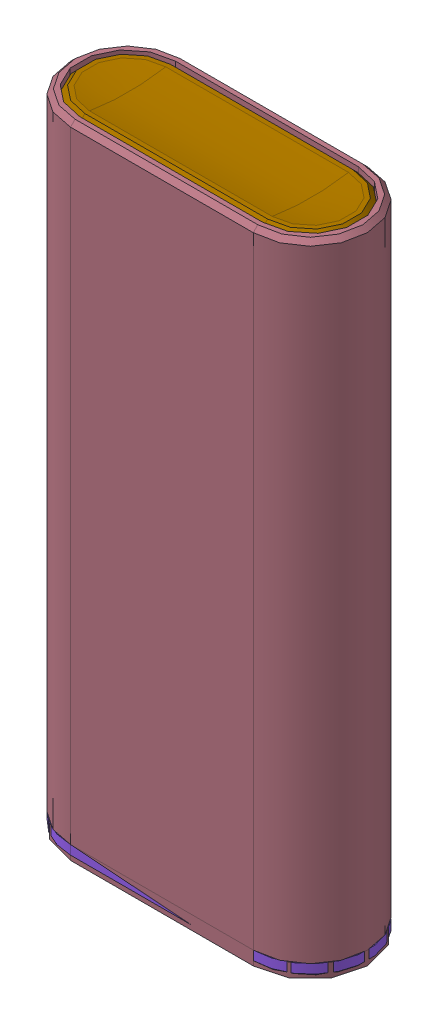
SolidWorks assembly case, configuration Default. Lengths in mm.
Overall size (65 140.17 25).
27 component instances, 14 part files, 68 mates.
Components (placement in the parent):
- touch_clamp-1: touch_clamp [Closed] at origin size (21.45 19 7)
  - touch_clamp-1: touch_clamp [Closed] at origin size (10.9 16.59 6.9)
  - touch_plate-1: touch_plate [Default] at (0 19 0) x (-1 0 0) z (0 0 1) size (21.45 7.3 7)
- 90710A030_TYPE 18-8 SS THIN HEX NUT - DIN 439B-1: 90710A030_TYPE 18-8 SS THIN HEX NUT - DIN 439B [90710A030] at (-7 22.9 0) x (0.5 0 -0.866025) z (0.866025 0 0.5) size (5.5 2.19 6.35)
- 92125A128_TYPE 18-8 SS FLAT-HEAD SOCKET CAP SCREW-1: 92125A128_TYPE 18-8 SS FLAT-HEAD SOCKET CAP SCREW [92125A128] at (-7 16.9084 0) x (-0.477813 0 -0.878461) z (0 -1 0) size (6 6 8.29)
- body-1: body [Default] at (-12.8586 33.4 -3.35) size (14.1 96 14.67)
  - body-1: body [Default] at origin size (14.1 96 14.1)
  - 92095A110_BUTTON HEAD HEX DRIVE SCREW-1: 92095A110_BUTTON HEAD HEX DRIVE SCREW [92095A110] at (0 4.7 7.55) size (3.5 3.5 3.5)
- tip-1: tip [Default] at (17.0932 46.5 -5.05) x (-1 0 0) z (0 0 -1) size (10.6 98.85 10.6)
- Shell_Base-1: Shell_Base [Default] at origin size (65 15.6 25)
- Case-1: Case [Default] at (0 19 0) x (-1 0 0) z (0 0 1) size (60.7 125.7 20.87)
- Clamp-1: Clamp [Body] at (-12.8586 43.4 -3.35) size (18 14 12.99)
- Clamp-2: Clamp [Body] at (-12.8586 116.4 -3.35) x (-1 0 0) z (0 0 1) size (18 14 12.99)
- Clamp-3: Clamp [Tip] at (17.0932 51.5 -5.05) size (13.4 14 9.61)
- 90710A030_TYPE 18-8 SS THIN HEX NUT - DIN 439B-2: 90710A030_TYPE 18-8 SS THIN HEX NUT - DIN 439B [90710A030] at (-12.8586 109.4 9.45) x (-0.866025 0.5 0) z (0.5 0.866025 0) size (5.5 2.19 6.35)
- 90710A030_TYPE 18-8 SS THIN HEX NUT - DIN 439B-3: 90710A030_TYPE 18-8 SS THIN HEX NUT - DIN 439B [90710A030] at (-12.8586 50.4 9.45) x (-0.866025 0.5 0) z (0.5 0.866025 0) size (5.5 2.19 6.35)
- 90710A030_TYPE 18-8 SS THIN HEX NUT - DIN 439B-4: 90710A030_TYPE 18-8 SS THIN HEX NUT - DIN 439B [90710A030] at (17.0932 58.5 9.45) x (-0.866025 0.5 0) z (0.5 0.866025 0) size (5.5 2.19 6.35)
- 90710A030_TYPE 18-8 SS THIN HEX NUT - DIN 439B-5: 90710A030_TYPE 18-8 SS THIN HEX NUT - DIN 439B [90710A030] at (7 22.9 0) x (0.5 0 -0.866025) z (0.866025 0 0.5) size (5.5 2.19 6.35)
- 92125A128_TYPE 18-8 SS FLAT-HEAD SOCKET CAP SCREW-2: 92125A128_TYPE 18-8 SS FLAT-HEAD SOCKET CAP SCREW [92125A128] at (7 16.9084 0) x (0.38424 0 0.923233) z (0 -1 0) size (6 6 8.29)
- 92125A125_TYPE 18-8 SS FLAT-HEAD SOCKET CAP SCREW-1: 92125A125_TYPE 18-8 SS FLAT-HEAD SOCKET CAP SCREW [92125A125] at (-12.8586 109.4 3.3) x (0.834265 -0.551364 0) z (0 0 -1) size (6 6 5.27)
- 92125A125_TYPE 18-8 SS FLAT-HEAD SOCKET CAP SCREW-2: 92125A125_TYPE 18-8 SS FLAT-HEAD SOCKET CAP SCREW [92125A125] at (-12.8586 50.4 3.3) x (0.247019 0.969011 0) z (0 0 -1) size (6 6 5.27)
- 92125A130_TYPE 18-8 SS FLAT-HEAD SOCKET CAP SCREW-1: 92125A130_TYPE 18-8 SS FLAT-HEAD SOCKET CAP SCREW [92125A130] at (17.0932 58.5 -0.7) x (-0.430385 -0.902645 0) z (0 0 -1) size (6 6 10.3)
- Shell_Wall-1: Shell_Wall [Default] at origin size (65 140 25)
- 90710A030_TYPE 18-8 SS THIN HEX NUT - DIN 439B-6: 90710A030_TYPE 18-8 SS THIN HEX NUT - DIN 439B [90710A030] at (20 2.3 0) x (0.866025 0 0.5) z (-0.5 0 0.866025) size (5.5 2.19 6.35)
- 90710A030_TYPE 18-8 SS THIN HEX NUT - DIN 439B-7: 90710A030_TYPE 18-8 SS THIN HEX NUT - DIN 439B [90710A030] at (-20 2.3 0) x (0.866025 0 0.5) z (-0.5 0 0.866025) size (5.5 2.19 6.35)
- 92125A126_TYPE 18-8 SS FLAT-HEAD SOCKET CAP SCREW-1: 92125A126_TYPE 18-8 SS FLAT-HEAD SOCKET CAP SCREW [92125A126] at (20 -3.65 0) x (0.790167 0 -0.612892) z (0 -1 0) size (6 6 6.28)
- 92125A126_TYPE 18-8 SS FLAT-HEAD SOCKET CAP SCREW-2: 92125A126_TYPE 18-8 SS FLAT-HEAD SOCKET CAP SCREW [92125A126] at (-19.9489 -3.65 0) x (1 0 0) z (0 -1 0) size (6 6 6.28)
Mates (geometry in assembly coordinates):
- Coincident1: coordinate: point of touch_clamp-1
- Parallel1: parallel aligned: plane of 90710A030_TYPE 18-8 SS THIN HEX NUT - DIN 439B-1 through (-9.75 23.8 -1.5877) normal (-1 0 0); plane of touch_clamp-1/touch_plate-1 through (-10.5 17 3.5) normal (-1 0 0)
- Concentric3: concentric anti-aligned: circle of touch_clamp-1/touch_plate-1; circle of 92125A128_TYPE 18-8 SS FLAT-HEAD SOCKET CAP SCREW-1
- Tangent3: tangent: face of ?; circle of 92125A128_TYPE 18-8 SS FLAT-HEAD SOCKET CAP SCREW-1
- Coincident4: coincident anti-aligned: plane of 90710A030_TYPE 18-8 SS THIN HEX NUT - DIN 439B-1 through (-9.75 22 1.5877) normal (0 -1 0); plane of Case-1 through (0 22 0) normal (0 1 0)
- Concentric4: concentric aligned: circle of 90710A030_TYPE 18-8 SS THIN HEX NUT - DIN 439B-1; circle of 92125A128_TYPE 18-8 SS FLAT-HEAD SOCKET CAP SCREW-1
- Distance1: distance: cylinder of tip-1 through (17.0932 68.5 -5.05) axis (0 -1 0) radius 4.2; cylinder of body-1/body-1 through (-12.8586 102.9 -3.35) axis (0 -1 0) radius 6.5
- Distance9: distance = 5 mm aligned: plane of body-1/body-1 through (-12.8586 33.4 -3.35) normal (0 -1 0); plane of tip-1 through (17.0932 28.4 -5.675) normal (0 -1 0)
- Parallel3: parallel aligned: plane of touch_clamp-1/touch_clamp-1 through (-3.95 12 -3.45) normal (0 0 -1); plane of body-1/body-1 through (-12.8586 46.6301 -8.61) normal (0 0 -1)
- Parallel4: parallel anti-aligned: plane of touch_clamp-1/touch_plate-1 through (-10.5 17 3.5) normal (-1 0 0); plane of body-1/body-1 through (-9.1261 68.3467 -8.61) normal (1 0 0)
- Coincident11: coordinate: unknown of Shell-1
- Coincident16: coordinate: point of touch_clamp-1/touch_plate-1; point of Case-1
- Concentric6: concentric anti-aligned: cylinder of body-1/body-1 through (-12.8586 102.9 -3.35) axis (0 -1 0) radius 6.5; cylinder of Clamp-2 through (-12.8586 102.4 -3.35) axis (0 1 0) radius 6.5
- Concentric7: concentric aligned: cylinder of body-1/body-1 through (-12.8586 102.9 -3.35) axis (0 -1 0) radius 6.5; cylinder of Clamp-1 through (-12.8586 57.4 -3.35) axis (0 -1 0) radius 6.5
- Parallel6: parallel aligned: plane of Clamp-1 through (-12.8586 57.4 6.7872) normal (0 0 1); plane of Clamp-2 through (-12.8586 102.4 6.7872) normal (0 0 1)
- Parallel7: parallel aligned: plane of body-1/body-1 through (-12.8586 46.6301 -8.61) normal (0 0 -1); plane of Case-1 through (-20 136.4 -10.35) normal (0 0 -1)
- Tangent5: tangent aligned: cylinder of body-1/body-1 through (-12.8586 125.6 -3.35) axis (0 1 0) radius 7; plane of Case-1 through (-20 136.4 -10.35) normal (0 0 -1)
- Parallel9: parallel aligned: plane of body-1/body-1 through (-12.8586 33.4 -3.35) normal (0 -1 0); plane of Case-1 through (20 19 0) normal (0 -1 0)
- Concentric8: concentric aligned: cylinder of tip-1 through (17.0932 68.5 -5.05) axis (0 -1 0) radius 4.2; cylinder of Clamp-3 through (17.0932 65.5 -5.05) axis (0 -1 0) radius 4.2
- Distance3: distance = 45 mm anti-aligned: plane of Clamp-2 through (-12.8586 102.4 -3.35) normal (0 -1 0); plane of Clamp-1 through (-12.8586 57.4 -3.35) normal (0 1 0)
- Parallel11: parallel aligned: plane of Case-1 through (20 136.4 10.35) normal (0 0 1); plane of Clamp-1 through (-12.8586 57.4 6.7872) normal (0 0 1)
- Parallel12: parallel aligned: plane of Case-1 through (20 136.4 10.35) normal (0 0 1); plane of Clamp-3 through (17.0932 65.5 2.4367) normal (0 0 1)
- Distance4: distance = 10 mm aligned: plane of Clamp-1 through (-12.8586 43.4 -3.35) normal (0 -1 0); plane of body-1/body-1 through (-12.8586 33.4 -3.35) normal (0 -1 0)
- Distance5: distance = 5 mm aligned: plane of Clamp-3 through (17.0932 51.5 -5.05) normal (0 -1 0); plane of tip-1 through (17.0932 46.5 -5.05) normal (0 -1 0)
- Tangent6: tangent aligned: cylinder of tip-1 through (17.0932 70.75 -5.05) axis (0 -1 0) radius 5.3; plane of Case-1 through (-20 136.4 -10.35) normal (0 0 -1)
- Parallel14: parallel: line of tip-1 through (15.9476 127.25 -5.55) axis (1 0 0); plane of Case-1 through (-20 136.4 -10.35) normal (0 0 -1)
- Distance6: distance = 7 mm aligned: plane of body-1/body-1 through (-12.8586 129.4 -3.35) normal (0 1 0); plane of Case-1 through (20 136.4 0) normal (0 1 0)
- Distance8: distance = 10 mm: cylinder of body-1/body-1 through (-12.8586 102.9 -3.35) axis (0 -1 0) radius 6.5; line of Case-1 through (-20 135.4 -10.35) axis (0 -1 0)
- Coincident33: coincident aligned: plane of Case-1 through (20 136.4 10.35) normal (0 0 1); plane of 90710A030_TYPE 18-8 SS THIN HEX NUT - DIN 439B-2 through (-11.2709 106.65 10.35) normal (0 0 1)
- Concentric11: concentric anti-aligned: circle of Clamp-2; circle of 90710A030_TYPE 18-8 SS THIN HEX NUT - DIN 439B-2
- Parallel18: parallel aligned: plane of Case-1 through (20 136.4 0) normal (0 1 0); plane of 90710A030_TYPE 18-8 SS THIN HEX NUT - DIN 439B-2 through (-11.2709 112.15 10.35) normal (0 1 0)
- Concentric12: concentric anti-aligned: circle of Clamp-1; circle of 90710A030_TYPE 18-8 SS THIN HEX NUT - DIN 439B-3
- Coincident36: coincident aligned: plane of Case-1 through (20 136.4 10.35) normal (0 0 1); plane of 90710A030_TYPE 18-8 SS THIN HEX NUT - DIN 439B-3 through (-11.2709 47.65 10.35) normal (0 0 1)
- Parallel19: parallel aligned: plane of Case-1 through (20 136.4 0) normal (0 1 0); plane of 90710A030_TYPE 18-8 SS THIN HEX NUT - DIN 439B-3 through (-11.2709 53.15 10.35) normal (0 1 0)
- Coincident38: coincident aligned: plane of Case-1 through (20 136.4 10.35) normal (0 0 1); plane of 90710A030_TYPE 18-8 SS THIN HEX NUT - DIN 439B-4 through (18.6809 55.75 10.35) normal (0 0 1)
- Concentric13: concentric anti-aligned: circle of Clamp-3; circle of 90710A030_TYPE 18-8 SS THIN HEX NUT - DIN 439B-4
- Parallel20: parallel aligned: plane of Case-1 through (20 136.4 0) normal (0 1 0); plane of 90710A030_TYPE 18-8 SS THIN HEX NUT - DIN 439B-4 through (18.6809 61.25 10.35) normal (0 1 0)
- Coincident40: coincident anti-aligned: plane of Case-1 through (0 22 0) normal (0 1 0); plane of 90710A030_TYPE 18-8 SS THIN HEX NUT - DIN 439B-5 through (4.25 22 1.5877) normal (0 -1 0)
- Concentric14: concentric anti-aligned: circle of touch_clamp-1/touch_plate-1; circle of 90710A030_TYPE 18-8 SS THIN HEX NUT - DIN 439B-5
- Coincident41: coincident aligned: plane of 92125A128_TYPE 18-8 SS FLAT-HEAD SOCKET CAP SCREW-1 through (-8.3177 16.9084 0.7167) normal (0 -1 0); plane of 92125A128_TYPE 18-8 SS FLAT-HEAD SOCKET CAP SCREW-2 through (8.3848 16.9084 -0.5764) normal (0 -1 0)
- Concentric15: concentric aligned: circle of touch_clamp-1/touch_plate-1; circle of 92125A128_TYPE 18-8 SS FLAT-HEAD SOCKET CAP SCREW-2
- Concentric16: concentric aligned: cylinder of Clamp-1 through (-12.8586 50.4 3.35) axis (0 0 -1) radius 1.8; circle of ?
- Coincident42: coincident aligned: cone of Clamp-1 through (-12.8586 50.4 3.35) axis (0 0 1); cylinder of ? through (-12.8586 50.4 5.15) axis (0 0 1) radius 785.3982
- Concentric17: concentric aligned: cylinder of Clamp-2 through (-12.8586 109.4 3.35) axis (0 0 -1) radius 1.8; cylinder of 92125A125_TYPE 18-8 SS FLAT-HEAD SOCKET CAP SCREW-1 through (-12.8586 109.4 3.3) axis (0 0 -1) radius 3
- Coincident43: coincident aligned: cylinder of Clamp-2 through (-12.8586 109.4 3.35) axis (0 0 1) radius 785.3982; cylinder of 92125A125_TYPE 18-8 SS FLAT-HEAD SOCKET CAP SCREW-1 through (-12.8586 109.4 5) axis (0 0 1) radius 785.3982
- Concentric18: concentric aligned: cylinder of Clamp-1 through (-12.8586 50.4 3.35) axis (0 0 -1) radius 1.8; cylinder of 92125A125_TYPE 18-8 SS FLAT-HEAD SOCKET CAP SCREW-2 through (-12.8586 50.4 3.3) axis (0 0 -1) radius 3
- Coincident44: coincident aligned: cylinder of Clamp-1 through (-12.8586 50.4 3.35) axis (0 0 1) radius 785.3982; cylinder of 92125A125_TYPE 18-8 SS FLAT-HEAD SOCKET CAP SCREW-2 through (-12.8586 50.4 5) axis (0 0 1) radius 785.3982
- Concentric19: concentric aligned: cylinder of Clamp-3 through (17.0932 58.5 -0.65) axis (0 0 -1) radius 1.8; cylinder of ? through (17.0932 58.5 -0.55) axis (0 0 -1) radius 3
- Coincident45: coincident aligned: cylinder of Clamp-3 through (17.0932 58.5 -0.65) axis (0 0 1) radius 785.3982; cylinder of ? through (17.0932 58.5 1.15) axis (0 0 1) radius 785.3982
- Concentric20: concentric aligned: cylinder of Clamp-3 through (17.0932 58.5 -0.65) axis (0 0 -1) radius 1.8; cylinder of 92125A130_TYPE 18-8 SS FLAT-HEAD SOCKET CAP SCREW-1 through (17.0932 58.5 -0.7) axis (0 0 -1) radius 3
- Coincident46: coincident aligned: cylinder of Clamp-3 through (17.0932 58.5 -0.65) axis (0 0 1) radius 785.3982; cylinder of 92125A130_TYPE 18-8 SS FLAT-HEAD SOCKET CAP SCREW-1 through (17.0932 58.5 1) axis (0 0 1) radius 785.3982
- Coincident47: coincident anti-aligned: plane of Shell_Base-1 through (-20 -0.6 0) normal (0 1 0); plane of Shell_Wall-1 through (-20 -0.6 0) normal (0 -1 0)
- Concentric21: concentric aligned: cylinder of Shell_Base-1 through (20 -3.6 0) axis (0 -1 0) radius 1.8; cylinder of Shell_Wall-1 through (20 -0.6 0) axis (0 -1 0) radius 1.8
- Coincident48: coincident aligned: plane of Shell_Base-1 through (-20 -3.6 -12.5) normal (0 0 -1); plane of Shell_Wall-1 through (20 136.4 -12.5) normal (0 0 -1)
- Concentric22: concentric anti-aligned: circle of Shell_Wall-1; circle of 90710A030_TYPE 18-8 SS THIN HEX NUT - DIN 439B-6
- Concentric23: concentric anti-aligned: circle of Shell_Wall-1; circle of 90710A030_TYPE 18-8 SS THIN HEX NUT - DIN 439B-7
- Parallel21: parallel aligned: plane of Shell_Wall-1 through (0 4.4 2.85) normal (0 0 -1); plane of 90710A030_TYPE 18-8 SS THIN HEX NUT - DIN 439B-6 through (21.5877 3.2 -2.75) normal (0 0 -1)
- Parallel22: parallel aligned: plane of Shell_Wall-1 through (0 4.4 2.85) normal (0 0 -1); plane of 90710A030_TYPE 18-8 SS THIN HEX NUT - DIN 439B-7 through (-18.4123 3.2 -2.75) normal (0 0 -1)
- Coincident51: coincident: line of Shell_Wall-1 through (14.45 1.4 -2.85) axis (0 0 1); plane of 90710A030_TYPE 18-8 SS THIN HEX NUT - DIN 439B-6 through (18.4123 1.4 -2.75) normal (0 -1 0)
- Coincident52: coincident: line of Shell_Wall-1 through (-14.45 1.4 -2.85) axis (0 0 1); plane of 90710A030_TYPE 18-8 SS THIN HEX NUT - DIN 439B-7 through (-21.5877 1.4 -2.75) normal (0 -1 0)
- Concentric24: concentric aligned: circle of Shell_Base-1; circle of 92125A130_TYPE 18-8 SS FLAT-HEAD SOCKET CAP SCREW-3
- Concentric25: concentric aligned: circle of Shell_Base-1; circle of 92125A130_TYPE 18-8 SS FLAT-HEAD SOCKET CAP SCREW-2
- Coincident54: coincident aligned: cylinder of Shell_Base-1 through (-19.9489 -3.6 0) axis (0 1 0) radius 785.3982; cylinder of 92125A130_TYPE 18-8 SS FLAT-HEAD SOCKET CAP SCREW-2 through (-19.9489 -1.95 0) axis (0 1 0) radius 785.3982
- Coincident55: coincident aligned: cylinder of Shell_Base-1 through (20 -3.6 0) axis (0 1 0) radius 785.3982; cylinder of 92125A130_TYPE 18-8 SS FLAT-HEAD SOCKET CAP SCREW-3 through (20 -1.95 0) axis (0 1 0) radius 785.3982
- Concentric26: concentric aligned: circle of Shell_Base-1; circle of 92125A126_TYPE 18-8 SS FLAT-HEAD SOCKET CAP SCREW-1
- Coincident56: coincident aligned: cylinder of Shell_Base-1 through (20 -3.6 0) axis (0 1 0) radius 785.3982; cylinder of 92125A126_TYPE 18-8 SS FLAT-HEAD SOCKET CAP SCREW-1 through (20 -1.95 0) axis (0 1 0) radius 785.3982
- Concentric27: concentric aligned: circle of Shell_Base-1; circle of 92125A126_TYPE 18-8 SS FLAT-HEAD SOCKET CAP SCREW-2
- Coincident57: coincident aligned: cylinder of Shell_Base-1 through (-19.9489 -3.6 0) axis (0 1 0) radius 785.3982; cylinder of 92125A126_TYPE 18-8 SS FLAT-HEAD SOCKET CAP SCREW-2 through (-19.9489 -1.95 0) axis (0 1 0) radius 785.3982
